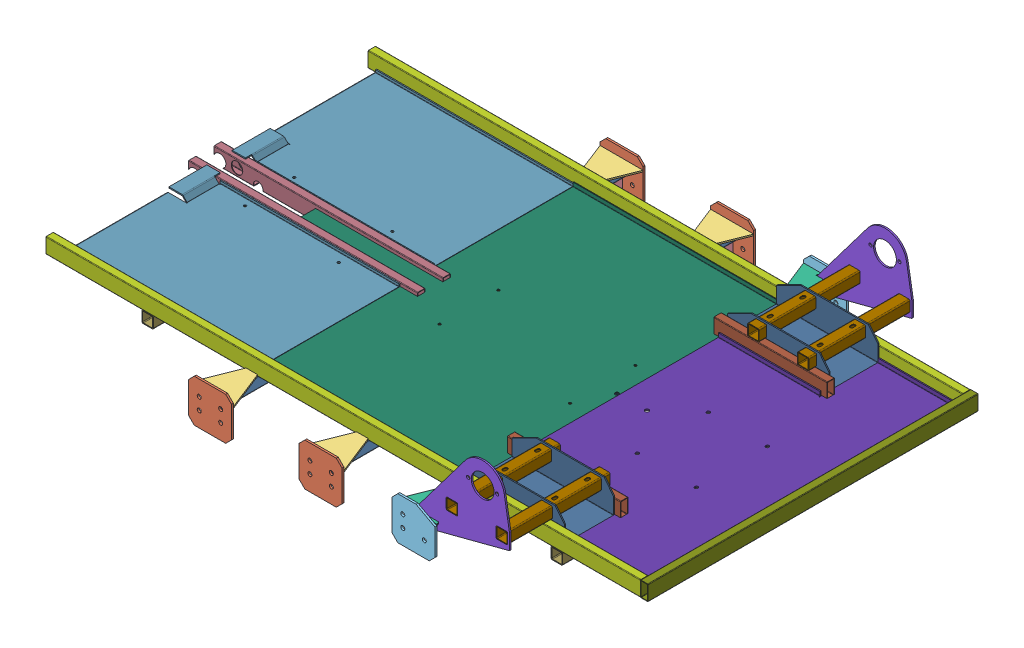
SolidWorks assembly ТП.016.01.01.01.00 - Рама корпуса, configuration 00. Lengths in mm.
Overall size (1585 284.02 1098).
72 component instances, 19 part files, 73 mates.
Components (placement in the parent):
- ТП.016.01.01.01.01.00 - Поперечная балка в сборе-1: ТП.016.01.01.01.01.00 - Поперечная балка в сборе [Центральная] at (824.8534 -30 544) size (112 110.77 1078)
  - ТП.016.01.01.01.01.01 - Поперечная балка (30х30)-1: ТП.016.01.01.01.01.01 - Поперечная балка (30х30) [--] at origin size (30 30 1068)
  - ТП.016.01.01.01.01.02 - Пластина кронштейна (5мм)-1: ТП.016.01.01.01.01.02 - Пластина кронштейна (5мм) [--] at (0 -56.7738 -5) size (112 110.77 5)
  - ТП.016.01.01.01.01.03 - Косынка верхняя (4мм)-1: ТП.016.01.01.01.01.03 - Косынка верхняя (4мм) [--] at (0 30 -10) size (112 4 104)
  - ТП.016.01.01.01.01.02 - Пластина кронштейна (5мм)-2: ТП.016.01.01.01.01.02 - Пластина кронштейна (5мм) [--] at (0 -56.7738 -1083) x (-1 0 0) z (0 0 -1) size (112 110.77 5)
  - ТП.016.01.01.01.01.03 - Косынка верхняя (4мм)-2: ТП.016.01.01.01.01.03 - Косынка верхняя (4мм) [--] at (0 30 -1078) x (-1 0 0) z (0 0 -1) size (112 4 104)
  - ТП.016.01.01.01.01.04 - Косынка нижняя (4мм)-2: ТП.016.01.01.01.01.04 - Косынка нижняя (4мм) [--] at (0 0 -1078) x (-1 0 0) z (0 0 -1) size (4 53.77 53.77)
  - ТП.016.01.01.01.01.04 - Косынка нижняя (4мм)-3: ТП.016.01.01.01.01.04 - Косынка нижняя (4мм) [--] at (0 0 -10) size (4 53.77 53.77)
  - ТП.016.01.01.01.01.05 - Пластина кронштейна задняя (5мм)-1: ТП.016.01.01.01.01.05 - Пластина кронштейна задняя (5мм) [--] at (0 -56.7738 -1083) x (-1 0 0) z (0 0 -1) size (112 110.77 5) (hidden)
  - ТП.016.01.01.01.01.06 - Косынка верхняя задняя (4мм)-1: ТП.016.01.01.01.01.06 - Косынка верхняя задняя (4мм) [--] at (-15 30 -1078) x (-1 0 0) z (0 0 -1) size (111.99 4 104) (hidden)
  - ТП.016.01.01.01.01.05 - Пластина кронштейна задняя (5мм)-2: ТП.016.01.01.01.01.05 - Пластина кронштейна задняя (5мм) [--] at (0 -56.7738 -10) x (-1 0 0) z (0 0 -1) size (112 110.77 5) (hidden)
  - ТП.016.01.01.01.01.06 - Косынка верхняя задняя (4мм)-2: ТП.016.01.01.01.01.06 - Косынка верхняя задняя (4мм) [--] at (-15 34 -10) x (-1 0 0) z (0 0 1) size (111.99 4 104) (hidden)
- ТП.016.01.01.01.01.00 - Поперечная балка в сборе-2: ТП.016.01.01.01.01.00 - Поперечная балка в сборе [Центральная] at (536.5267 -30 544) size (112 110.77 1078)
  - ТП.016.01.01.01.01.01 - Поперечная балка (30х30)-1: ТП.016.01.01.01.01.01 - Поперечная балка (30х30) [--] at origin size (30 30 1068)
  - ТП.016.01.01.01.01.02 - Пластина кронштейна (5мм)-1: ТП.016.01.01.01.01.02 - Пластина кронштейна (5мм) [--] at (0 -56.7738 -5) size (112 110.77 5)
  - ТП.016.01.01.01.01.03 - Косынка верхняя (4мм)-1: ТП.016.01.01.01.01.03 - Косынка верхняя (4мм) [--] at (0 30 -10) size (112 4 104)
  - ТП.016.01.01.01.01.02 - Пластина кронштейна (5мм)-2: ТП.016.01.01.01.01.02 - Пластина кронштейна (5мм) [--] at (0 -56.7738 -1083) x (-1 0 0) z (0 0 -1) size (112 110.77 5)
  - ТП.016.01.01.01.01.03 - Косынка верхняя (4мм)-2: ТП.016.01.01.01.01.03 - Косынка верхняя (4мм) [--] at (0 30 -1078) x (-1 0 0) z (0 0 -1) size (112 4 104)
  - ТП.016.01.01.01.01.04 - Косынка нижняя (4мм)-2: ТП.016.01.01.01.01.04 - Косынка нижняя (4мм) [--] at (0 0 -1078) x (-1 0 0) z (0 0 -1) size (4 53.77 53.77)
  - ТП.016.01.01.01.01.04 - Косынка нижняя (4мм)-3: ТП.016.01.01.01.01.04 - Косынка нижняя (4мм) [--] at (0 0 -10) size (4 53.77 53.77)
  - ТП.016.01.01.01.01.05 - Пластина кронштейна задняя (5мм)-1: ТП.016.01.01.01.01.05 - Пластина кронштейна задняя (5мм) [--] at (0 -56.7738 -1083) x (-1 0 0) z (0 0 -1) size (112 110.77 5) (hidden)
  - ТП.016.01.01.01.01.06 - Косынка верхняя задняя (4мм)-1: ТП.016.01.01.01.01.06 - Косынка верхняя задняя (4мм) [--] at (-15 30 -1078) x (-1 0 0) z (0 0 -1) size (111.99 4 104) (hidden)
  - ТП.016.01.01.01.01.05 - Пластина кронштейна задняя (5мм)-2: ТП.016.01.01.01.01.05 - Пластина кронштейна задняя (5мм) [--] at (0 -56.7738 -10) x (-1 0 0) z (0 0 -1) size (112 110.77 5) (hidden)
  - ТП.016.01.01.01.01.06 - Косынка верхняя задняя (4мм)-2: ТП.016.01.01.01.01.06 - Косынка верхняя задняя (4мм) [--] at (-15 34 -10) x (-1 0 0) z (0 0 1) size (111.99 4 104) (hidden)
- ТП.016.01.01.01.01.00 - Поперечная балка в сборе-3: ТП.016.01.01.01.01.00 - Поперечная балка в сборе [Задняя] at (1067.2668 -30 544) size (112 110.77 1078)
  - ТП.016.01.01.01.01.01 - Поперечная балка (30х30)-1: ТП.016.01.01.01.01.01 - Поперечная балка (30х30) [Под лебедку] at origin size (30 30 1068)
  - ТП.016.01.01.01.01.02 - Пластина кронштейна (5мм)-1: ТП.016.01.01.01.01.02 - Пластина кронштейна (5мм) [--] at (0 -56.7738 -5) size (112 110.77 5) (hidden)
  - ТП.016.01.01.01.01.03 - Косынка верхняя (4мм)-1: ТП.016.01.01.01.01.03 - Косынка верхняя (4мм) [--] at (0 30 -10) size (112 4 104) (hidden)
  - ТП.016.01.01.01.01.02 - Пластина кронштейна (5мм)-2: ТП.016.01.01.01.01.02 - Пластина кронштейна (5мм) [--] at (0 -56.7738 -1083) x (-1 0 0) z (0 0 -1) size (112 110.77 5) (hidden)
  - ТП.016.01.01.01.01.03 - Косынка верхняя (4мм)-2: ТП.016.01.01.01.01.03 - Косынка верхняя (4мм) [--] at (0 30 -1078) x (-1 0 0) z (0 0 -1) size (112 4 104) (hidden)
  - ТП.016.01.01.01.01.04 - Косынка нижняя (4мм)-2: ТП.016.01.01.01.01.04 - Косынка нижняя (4мм) [--] at (0 0 -1078) x (-1 0 0) z (0 0 -1) size (4 53.77 53.77)
  - ТП.016.01.01.01.01.04 - Косынка нижняя (4мм)-3: ТП.016.01.01.01.01.04 - Косынка нижняя (4мм) [--] at (0 0 -10) size (4 53.77 53.77)
  - ТП.016.01.01.01.01.05 - Пластина кронштейна задняя (5мм)-1: ТП.016.01.01.01.01.05 - Пластина кронштейна задняя (5мм) [--] at (0 -56.7738 -1083) x (-1 0 0) z (0 0 -1) size (112 110.77 5)
  - ТП.016.01.01.01.01.06 - Косынка верхняя задняя (4мм)-1: ТП.016.01.01.01.01.06 - Косынка верхняя задняя (4мм) [--] at (-15 30 -1078) x (-1 0 0) z (0 0 -1) size (111.99 4 104)
  - ТП.016.01.01.01.01.05 - Пластина кронштейна задняя (5мм)-2: ТП.016.01.01.01.01.05 - Пластина кронштейна задняя (5мм) [--] at (0 -56.7738 -10) x (-1 0 0) z (0 0 -1) size (112 110.77 5)
  - ТП.016.01.01.01.01.06 - Косынка верхняя задняя (4мм)-2: ТП.016.01.01.01.01.06 - Косынка верхняя задняя (4мм) [--] at (-15 34 -10) x (-1 0 0) z (0 0 1) size (111.99 4 104)
- ТП.016.01.01.01.02 - Балка платформы боковая (40х20)-1: ТП.016.01.01.01.02 - Балка платформы боковая (40х20) [--] at (250 0 -420) x (0 0 -1) z (1 0 0) size (20 40 1550)
- ТП.016.01.01.01.02 - Балка платформы боковая (40х20)-2: ТП.016.01.01.01.02 - Балка платформы боковая (40х20) [--] at (250 0 420) x (0 0 -1) z (1 0 0) size (20 40 1550)
- Схема рамы ЭСКИЗ-1: Схема рамы ЭСКИЗ [--] x (0 0 -1) z (1 0 0) size (559 0 1052.27)
- ТП.016.01.01.01.03.00 - Опора редуктора-1: ТП.016.01.01.01.03.00 - Опора редуктора [Правая] at (1235 143.2262 -526.5) x (-1 0 0) z (0 0 -1) size (276.73 227.25 267.34)
  - ТП.016.01.01.01.03.01 - Щека ведущей оси (4мм)-1: ТП.016.01.01.01.03.01 - Щека ведущей оси (4мм) [--] at origin size (249.73 227.25 4)
  - ТП.016.01.01.01.03.02 - Балка опоры ребуктора (30х30)-1: ТП.016.01.01.01.03.02 - Балка опоры ребуктора (30х30) [--] at (65 -72 0) size (30 30 267.34)
  - ТП.016.01.01.01.03.02 - Балка опоры ребуктора (30х30)-2: ТП.016.01.01.01.03.02 - Балка опоры ребуктора (30х30) [--] at (-65 -72 0) size (30 30 267.34)
  - ТП.016.01.01.01.03.02 - Балка опоры ребуктора (30х30)-3: ТП.016.01.01.01.03.02 - Балка опоры ребуктора (30х30) [--] at (95 -72 -4) x (-1 0 0) z (0 0 -1) size (30 30 267.34) (hidden)
  - ТП.016.01.01.01.03.02 - Балка опоры ребуктора (30х30)-4: ТП.016.01.01.01.03.02 - Балка опоры ребуктора (30х30) [--] at (-35 -72 -4) x (-1 0 0) z (0 0 -1) size (30 30 267.34) (hidden)
  - ТП.016.01.01.01.03.03 - Пол под редуктор (3мм)-1: ТП.016.01.01.01.03.03 - Пол под редуктор (3мм) [--] at (65 -143.2262 -181.9182) x (0 0 -1) z (1 0 0) size (130.84 76.23 264.73)
- ТП.016.01.01.01.03.00 - Опора редуктора-2: ТП.016.01.01.01.03.00 - Опора редуктора [Левая] at (1235 143.2262 522.5) x (-1 0 0) z (0 0 -1) size (276.73 227.25 267.34)
  - ТП.016.01.01.01.03.01 - Щека ведущей оси (4мм)-1: ТП.016.01.01.01.03.01 - Щека ведущей оси (4мм) [--] at origin size (249.73 227.25 4)
  - ТП.016.01.01.01.03.02 - Балка опоры ребуктора (30х30)-1: ТП.016.01.01.01.03.02 - Балка опоры ребуктора (30х30) [--] at (65 -72 0) size (30 30 267.34) (hidden)
  - ТП.016.01.01.01.03.02 - Балка опоры ребуктора (30х30)-2: ТП.016.01.01.01.03.02 - Балка опоры ребуктора (30х30) [--] at (-65 -72 0) size (30 30 267.34) (hidden)
  - ТП.016.01.01.01.03.02 - Балка опоры ребуктора (30х30)-3: ТП.016.01.01.01.03.02 - Балка опоры ребуктора (30х30) [--] at (95 -72 -4) x (-1 0 0) z (0 0 -1) size (30 30 267.34)
  - ТП.016.01.01.01.03.02 - Балка опоры ребуктора (30х30)-4: ТП.016.01.01.01.03.02 - Балка опоры ребуктора (30х30) [--] at (-35 -72 -4) x (-1 0 0) z (0 0 -1) size (30 30 267.34)
  - ТП.016.01.01.01.03.03 - Пол под редуктор (3мм)-1: ТП.016.01.01.01.03.03 - Пол под редуктор (3мм) [--] at (65 -143.2262 177.9182) x (0 0 -1) z (1 0 0) size (130.84 76.23 264.73)
- ТП.016.01.01.01.04 - Опора короткая под редуктор (40х20)-1: ТП.016.01.01.01.04 - Опора короткая под редуктор (40х20) [--] at (1052.2668 0 -259.1637) x (0 0 -1) z (1 0 0) size (20 40 294.73)
- ТП.016.01.01.01.04 - Опора короткая под редуктор (40х20)-2: ТП.016.01.01.01.04 - Опора короткая под редуктор (40х20) [--] at (1052.2668 0 279.1637) x (0 0 -1) z (1 0 0) size (20 40 294.73)
- ТП.016.01.01.01.05 - Поперечина короткая (30х30)-1: ТП.016.01.01.01.05 - Поперечина короткая (30х30) [--] at (1347 0 0) size (30 30 860)
- ТП.016.01.01.01.05 - Поперечина короткая (30х30)-2: ТП.016.01.01.01.05 - Поперечина короткая (30х30) [--] at (280 0 0) size (30 30 860)
- ТП.016.01.01.01.06 - Поддержка центральная (40х20)-1: ТП.016.01.01.01.06 - Поддержка центральная (40х20) [--] at (45 -9.1741 -23) x (0 0 1) z (-1 0 0) size (20 40 596.53)
- ТП.016.01.01.01.06 - Поддержка центральная (40х20)-2: ТП.016.01.01.01.06 - Поддержка центральная (40х20) [--] at (45 -9.1741 43) x (0 0 1) z (-1 0 0) size (20 40 596.53)
- ТП.016.01.01.01.07 - Пол перед (3мм)-1: ТП.016.01.01.01.07 - Пол перед (3мм) [Правый] at (0 0 -410) x (0 0 -1) z (1 0 0) size (377 29.49 517.11)
- ТП.016.01.01.01.07 - Пол перед (3мм)-2: ТП.016.01.01.01.07 - Пол перед (3мм) [Левый] at (0 0 -344) x (0 0 -1) z (1 0 0) size (754 29.49 517.11)
- ТП.016.01.01.01.08 - Пол центр (2мм)-1: ТП.016.01.01.01.08 - Пол центр (2мм) [--] at (250 0 0) x (0 0 -1) z (1 0 0) size (820 12 817.27)
- ТП.016.01.01.01.09 - Задний бампер (40х20)-1: ТП.016.01.01.01.09 - Задний бампер (40х20) [--] at (1570 0 0) size (20 40 860)
- ТП.016.01.01.01.10 - Пол капота (3мм)-1: ТП.016.01.01.01.10 - Пол капота (3мм) [--] at (1550 0 0) x (0 0 1) z (-1 0 0) size (820 13 482.73)
- Гайка (ГОСТ ISO 4032-2014)-1: Гайка (ГОСТ ISO 4032-2014) [Гайка М6 (ГОСТ ISO 4032)] at (153.1386 -2.6 64.0253) x (-0.998033 0 -0.062689) z (0 1 0) size (10 11.05 5.2)
- Гайка (ГОСТ ISO 4032-2014)-2: Гайка (ГОСТ ISO 4032-2014) [Гайка М6 (ГОСТ ISO 4032)] at (403.0634 -2.6 70.156) x (-0.991964 0 0.126519) z (0 1 0) size (10 11.05 5.2)
- Гайка (ГОСТ ISO 4032-2014)-3: Гайка (ГОСТ ISO 4032-2014) [Гайка М6 (ГОСТ ISO 4032)] at (672.9822 -2.6 76.7772) x (-0.941367 0 0.337385) z (0 1 0) size (10 11.05 5.2)
- Гайка (ГОСТ ISO 4032-2014)-4: Гайка (ГОСТ ISO 4032-2014) [Гайка М6 (ГОСТ ISO 4032)] at (1021.6211 -2.6 85.3294) x (-0.83604 0 0.548669) z (0 1 0) size (10 11.05 5.2)
- Гайка (ГОСТ ISO 4032-2014)-5: Гайка (ГОСТ ISO 4032-2014) [Гайка М6 (ГОСТ ISO 4032)] at (1021.6211 -2.6 -85.3294) x (-0.680834 0 0.732437) z (0 1 0) size (10 11.05 5.2)
- Гайка (ГОСТ ISO 4032-2014)-6: Гайка (ГОСТ ISO 4032-2014) [Гайка М6 (ГОСТ ISO 4032)] at (672.9822 -2.6 -76.7772) x (-0.498939 0 0.866637) z (0 1 0) size (10 11.05 5.2)
- Гайка (ГОСТ ISO 4032-2014)-7: Гайка (ГОСТ ISO 4032-2014) [Гайка М6 (ГОСТ ISO 4032)] at (403.0634 -2.6 -70.156) x (-0.323185 0 0.946336) z (0 1 0) size (10 11.05 5.2)
- Гайка (ГОСТ ISO 4032-2014)-8: Гайка (ГОСТ ISO 4032-2014) [Гайка М6 (ГОСТ ISO 4032)] at (153.1386 -2.6 -64.0253) x (-0.182176 0 0.983266) z (0 1 0) size (10 11.05 5.2)
Mates (geometry in assembly coordinates):
- Совпадение1: coincident: plane of ТП.016.01.01.01.01.00 - Поперечная балка в сборе-1/ТП.016.01.01.01.01.01 - Поперечная балка (30х30)-1 through (836.8534 0 -492.4264) normal (0 1 0); plane of ТП.016.01.01.01.01.00 - Поперечная балка в сборе-2/ТП.016.01.01.01.01.01 - Поперечная балка (30х30)-1 through (548.5267 0 -492.4264) normal (0 1 0)
- Совпадение2: coincident: plane of ТП.016.01.01.01.01.00 - Поперечная балка в сборе-1/ТП.016.01.01.01.01.02 - Пластина кронштейна (5мм)-2 through (824.8534 -86.7738 -539) normal (0 0 -1); plane of ТП.016.01.01.01.01.00 - Поперечная балка в сборе-2/ТП.016.01.01.01.01.02 - Пластина кронштейна (5мм)-2 through (536.5267 -86.7738 -539) normal (0 0 -1)
- Совпадение3: coincident: plane of ТП.016.01.01.01.01.00 - Поперечная балка в сборе-2/ТП.016.01.01.01.01.01 - Поперечная балка (30х30)-1 through (548.5267 0 -492.4264) normal (0 1 0); plane of ТП.016.01.01.01.01.00 - Поперечная балка в сборе-3/ТП.016.01.01.01.01.01 - Поперечная балка (30х30)-1 through (1079.2668 0 -492.4264) normal (0 1 0)
- Совпадение4: coincident: plane of ТП.016.01.01.01.01.00 - Поперечная балка в сборе-2/ТП.016.01.01.01.01.02 - Пластина кронштейна (5мм)-2 through (536.5267 -86.7738 -539) normal (0 0 -1); plane of ТП.016.01.01.01.01.00 - Поперечная балка в сборе-3/ТП.016.01.01.01.01.05 - Пластина кронштейна задняя (5мм)-1 through (1067.2668 -86.7738 -539) normal (0 0 -1)
- Совпадение5: coincident: plane of ТП.016.01.01.01.01.00 - Поперечная балка в сборе-1/ТП.016.01.01.01.01.01 - Поперечная балка (30х30)-1 through (836.8534 0 -492.4264) normal (0 1 0); plane of ТП.016.01.01.01.02 - Балка платформы боковая (40х20)-1 through (0 0 -411.5) normal (0 -1 0)
- Совпадение6: coincident: plane of ТП.016.01.01.01.01.00 - Поперечная балка в сборе-2/ТП.016.01.01.01.01.03 - Косынка верхняя (4мм)-2 through (521.5267 4 -430) normal (0 0 1); plane of ТП.016.01.01.01.02 - Балка платформы боковая (40х20)-1 through (0 38.5 -430) normal (0 0 -1)
- Совпадение7: coincident: plane of ТП.016.01.01.01.01.00 - Поперечная балка в сборе-2/ТП.016.01.01.01.01.01 - Поперечная балка (30х30)-1 through (548.5267 0 -492.4264) normal (0 1 0); plane of ТП.016.01.01.01.02 - Балка платформы боковая (40х20)-2 through (0 0 428.5) normal (0 -1 0)
- Совпадение8: coincident: plane of ТП.016.01.01.01.02 - Балка платформы боковая (40х20)-1 through (1550 38.5 -428.5) normal (1 0 0); plane of ТП.016.01.01.01.02 - Балка платформы боковая (40х20)-2 through (1550 38.5 411.5) normal (1 0 0)
- Совпадение9: coincident: plane of ТП.016.01.01.01.01.00 - Поперечная балка в сборе-2/ТП.016.01.01.01.01.03 - Косынка верхняя (4мм)-1 through (551.5267 4 430) normal (0 0 -1); plane of ТП.016.01.01.01.02 - Балка платформы боковая (40х20)-2 through (0 38.5 430) normal (0 0 1)
- Совпадение14: coincident: plane of Схема рамы ЭСКИЗ-1 through (0 0 0) normal (0 0 -1); plane of assembly through (0 0 0) normal (0 0 1)
- Совпадение15: coincident: plane of Схема рамы ЭСКИЗ-1 through (0 0 0) normal (0 1 0); plane of assembly through (0 0 0) normal (0 1 0)
- Совпадение16: coincident: plane of Схема рамы ЭСКИЗ-1 through (0 0 0) normal (1 0 0); plane of assembly through (0 0 0) normal (1 0 0)
- Совпадение17: coincident: plane of ТП.016.01.01.01.01.00 - Поперечная балка в сборе-1/ТП.016.01.01.01.01.01 - Поперечная балка (30х30)-1 through (809.8534 -27 -492.4264) normal (-1 0 0); line of Схема рамы ЭСКИЗ-1 through (809.8534 0 0) axis (0 0 -1)
- Совпадение18: coincident: plane of ТП.016.01.01.01.01.00 - Поперечная балка в сборе-1/ТП.016.01.01.01.01.01 - Поперечная балка (30х30)-1 through (836.8534 0 -492.4264) normal (0 1 0); plane of assembly through (0 0 0) normal (0 1 0)
- Совпадение19: coincident: plane of ТП.016.01.01.01.01.00 - Поперечная балка в сборе-3/ТП.016.01.01.01.01.01 - Поперечная балка (30х30)-1 through (1052.2668 -27 -492.4264) normal (-1 0 0); line of Схема рамы ЭСКИЗ-1 through (1052.2668 0 0) axis (0 0 -1)
- Совпадение20: coincident: plane of ТП.016.01.01.01.01.00 - Поперечная балка в сборе-2/ТП.016.01.01.01.01.01 - Поперечная балка (30х30)-1 through (521.5267 -27 -492.4264) normal (-1 0 0); line of Схема рамы ЭСКИЗ-1 through (521.5267 0 0) axis (0 0 -1)
- Совпадение21: coincident: plane of ТП.016.01.01.01.02 - Балка платформы боковая (40х20)-1 through (0 38.5 -428.5) normal (-1 0 0); point of Схема рамы ЭСКИЗ-1
- Симметричный1: symmetric: plane of ТП.016.01.01.01.01.00 - Поперечная балка в сборе-2/ТП.016.01.01.01.01.02 - Пластина кронштейна (5мм)-1 through (536.5267 -86.7738 539) normal (0 0 1); plane of ? through (536.5267 -86.7738 -539) normal (0 0 -1)
- Совпадение22: coincident: plane of ТП.016.01.01.01.01.00 - Поперечная балка в сборе-3/ТП.016.01.01.01.01.01 - Поперечная балка (30х30)-1 through (1082.2668 -27 -492.4264) normal (1 0 0); plane of ТП.016.01.01.01.03.00 - Опора редуктора-1/ТП.016.01.01.01.03.01 - Щека ведущей оси (4мм)-1 through (1082.2668 -3 -522.5) normal (-1 0 0)
- Совпадение23: coincident: plane of ТП.016.01.01.01.01.00 - Поперечная балка в сборе-3/ТП.016.01.01.01.01.01 - Поперечная балка (30х30)-1 through (1079.2668 0 -492.4264) normal (0 1 0); plane of ТП.016.01.01.01.03.00 - Опора редуктора-1/ТП.016.01.01.01.03.01 - Щека ведущей оси (4мм)-1 through (1055.2668 0 -522.5) normal (0 -1 0)
- Совпадение24: coincident: plane of ТП.016.01.01.01.01.00 - Поперечная балка в сборе-3/ТП.016.01.01.01.01.06 - Косынка верхняя задняя (4мм)-1 through (1079.2668 -3 -526.5) normal (0 0 1); plane of ТП.016.01.01.01.03.00 - Опора редуктора-1/ТП.016.01.01.01.03.01 - Щека ведущей оси (4мм)-1 through (1079.2668 -3 -526.5) normal (0 0 -1)
- Совпадение25: coincident: plane of ТП.016.01.01.01.01.00 - Поперечная балка в сборе-3/ТП.016.01.01.01.01.01 - Поперечная балка (30х30)-1 through (1082.2668 -27 -492.4264) normal (1 0 0); plane of ТП.016.01.01.01.03.00 - Опора редуктора-2/ТП.016.01.01.01.03.01 - Щека ведущей оси (4мм)-1 through (1082.2668 -3 526.5) normal (-1 0 0)
- Совпадение26: coincident: plane of ТП.016.01.01.01.01.00 - Поперечная балка в сборе-3/ТП.016.01.01.01.01.01 - Поперечная балка (30х30)-1 through (1079.2668 0 -492.4264) normal (0 1 0); plane of ТП.016.01.01.01.03.00 - Опора редуктора-2/ТП.016.01.01.01.03.01 - Щека ведущей оси (4мм)-1 through (1055.2668 0 526.5) normal (0 -1 0)
- Совпадение27: coincident: plane of ТП.016.01.01.01.01.00 - Поперечная балка в сборе-3/ТП.016.01.01.01.01.06 - Косынка верхняя задняя (4мм)-2 through (1079.2668 7 526.5) normal (0 0 -1); plane of ТП.016.01.01.01.03.00 - Опора редуктора-2/ТП.016.01.01.01.03.01 - Щека ведущей оси (4мм)-1 through (1079.2668 -3 526.5) normal (0 0 1)
- Совпадение28: coincident: plane of ТП.016.01.01.01.01.00 - Поперечная балка в сборе-3/ТП.016.01.01.01.01.01 - Поперечная балка (30х30)-1 through (1079.2668 0 -492.4264) normal (0 1 0); plane of ТП.016.01.01.01.04 - Опора короткая под редуктор (40х20)-1 through (1401.7214 0 -277.6637) normal (0 -1 0)
- Совпадение29: coincident: plane of ТП.016.01.01.01.03.00 - Опора редуктора-1/ТП.016.01.01.01.03.02 - Балка опоры ребуктора (30х30)-1 through (1133 215.2262 -259.1637) normal (0 0 1); plane of ТП.016.01.01.01.04 - Опора короткая под редуктор (40х20)-1 through (1401.7214 1.5 -259.1637) normal (0 0 1)
- Совпадение30: coincident: plane of ТП.016.01.01.01.01.00 - Поперечная балка в сборе-3/ТП.016.01.01.01.01.01 - Поперечная балка (30х30)-1 through (1052.2668 -27 -492.4264) normal (-1 0 0); plane of ТП.016.01.01.01.04 - Опора короткая под редуктор (40х20)-1 through (1052.2668 1.5 -260.6637) normal (-1 0 0)
- Совпадение31: coincident: plane of ТП.016.01.01.01.04 - Опора короткая под редуктор (40х20)-1 through (1401.7214 40 -277.6637) normal (0 1 0); plane of ТП.016.01.01.01.04 - Опора короткая под редуктор (40х20)-2 through (1401.7214 40 260.6637) normal (0 1 0)
- Совпадение32: coincident: plane of ТП.016.01.01.01.01.00 - Поперечная балка в сборе-3/ТП.016.01.01.01.01.01 - Поперечная балка (30х30)-1 through (1052.2668 -27 -492.4264) normal (-1 0 0); plane of ТП.016.01.01.01.04 - Опора короткая под редуктор (40х20)-2 through (1052.2668 1.5 277.6637) normal (-1 0 0)
- Совпадение33: coincident: plane of ТП.016.01.01.01.03.00 - Опора редуктора-2/ТП.016.01.01.01.03.02 - Балка опоры ребуктора (30х30)-4 through (1307 215.2262 259.1637) normal (0 0 -1); plane of ТП.016.01.01.01.04 - Опора короткая под редуктор (40х20)-2 through (1401.7214 1.5 259.1637) normal (0 0 -1)
- Совпадение34: coincident: plane of ТП.016.01.01.01.04 - Опора короткая под редуктор (40х20)-2 through (1401.7214 0 260.6637) normal (0 -1 0); plane of ТП.016.01.01.01.05 - Поперечина короткая (30х30)-1 through (1320 0 472.4264) normal (0 1 0)
- Совпадение35: coincident: plane of ТП.016.01.01.01.04 - Опора короткая под редуктор (40х20)-2 through (1347 170 293.1637) normal (1 0 0); plane of ТП.016.01.01.01.05 - Поперечина короткая (30х30)-1 through (1347 -3 472.4264) normal (1 0 0)
- Совпадение36: coincident: plane of ТП.016.01.01.01.02 - Балка платформы боковая (40х20)-2 through (0 38.5 430) normal (0 0 1); plane of ТП.016.01.01.01.05 - Поперечина короткая (30х30)-1 through (1114 38.5 430) normal (0 0 1)
- Совпадение37: coincident: plane of ТП.016.01.01.01.05 - Поперечина короткая (30х30)-1 through (1320 0 472.4264) normal (0 1 0); plane of ТП.016.01.01.01.05 - Поперечина короткая (30х30)-2 through (253 0 472.4264) normal (0 1 0)
- Совпадение38: coincident: point of ТП.016.01.01.01.02 - Балка платформы боковая (40х20)-2; plane of ТП.016.01.01.01.05 - Поперечина короткая (30х30)-2 through (250 -3 472.4264) normal (-1 0 0)
- Совпадение39: coincident: plane of ТП.016.01.01.01.02 - Балка платформы боковая (40х20)-2 through (0 38.5 430) normal (0 0 1); plane of ТП.016.01.01.01.05 - Поперечина короткая (30х30)-2 through (47 38.5 430) normal (0 0 1)
- Совпадение40: coincident: plane of ТП.016.01.01.01.05 - Поперечина короткая (30х30)-2 through (253 0 472.4264) normal (0 1 0); plane of ТП.016.01.01.01.06 - Поддержка центральная (40х20)-1 through (253 0 472.4264) normal (0 -1 0)
- Совпадение41: coincident: plane of ТП.016.01.01.01.01.00 - Поперечная балка в сборе-2/ТП.016.01.01.01.01.01 - Поперечная балка (30х30)-1 through (521.5267 -27 -492.4264) normal (-1 0 0); plane of ТП.016.01.01.01.06 - Поддержка центральная (40х20)-1 through (521.5267 -3 492.4264) normal (1 0 0)
- Совпадение42: coincident: plane of ТП.016.01.01.01.01.00 - Поперечная балка в сборе-2/ТП.016.01.01.01.01.01 - Поперечная балка (30х30)-1 through (521.5267 -27 -492.4264) normal (-1 0 0); plane of ТП.016.01.01.01.06 - Поддержка центральная (40х20)-2 through (521.5267 -3 558.4264) normal (1 0 0)
- Совпадение43: coincident: plane of ТП.016.01.01.01.06 - Поддержка центральная (40х20)-1 through (-15 10.8259 -24.5) normal (0 1 0); plane of ТП.016.01.01.01.06 - Поддержка центральная (40х20)-2 through (-15 10.8259 41.5) normal (0 1 0)
- Совпадение44: coincident: plane of ТП.016.01.01.01.05 - Поперечина короткая (30х30)-2 through (253 0 472.4264) normal (0 1 0); plane of ТП.016.01.01.01.07 - Пол перед (3мм)-1 through (0 0 -410) normal (0 -1 0)
- Совпадение45: coincident: plane of ТП.016.01.01.01.06 - Поддержка центральная (40х20)-1 through (-15 -27.6741 -43) normal (0 0 -1); plane of ТП.016.01.01.01.07 - Пол перед (3мм)-1 through (0 0 -43) normal (0 0 1)
- Совпадение47: coincident: plane of ТП.016.01.01.01.02 - Балка платформы боковая (40х20)-1 through (0 38.5 -410) normal (0 0 1); plane of ТП.016.01.01.01.07 - Пол перед (3мм)-1 through (0 0 -410) normal (0 0 -1)
- Симметричный2: symmetric: plane of ТП.016.01.01.01.01.00 - Поперечная балка в сборе-2/ТП.016.01.01.01.01.01 - Поперечная балка (30х30)-1 through (551.5267 -27 -492.4264) normal (1 0 0); plane of ТП.016.01.01.01.01.00 - Поперечная балка в сборе-2/ТП.016.01.01.01.01.01 - Поперечная балка (30х30)-1 through (521.5267 -27 -492.4264) normal (-1 0 0); plane of ТП.016.01.01.01.07 - Пол перед (3мм)-1 through (536.5267 3 -43) normal (1 0 0)
- Совпадение48: coincident: plane of ТП.016.01.01.01.05 - Поперечина короткая (30х30)-2 through (253 0 472.4264) normal (0 1 0); plane of ТП.016.01.01.01.07 - Пол перед (3мм)-2 through (0 0 410) normal (0 -1 0)
- Совпадение49: coincident: plane of ТП.016.01.01.01.02 - Балка платформы боковая (40х20)-2 through (0 38.5 410) normal (0 0 -1); plane of ТП.016.01.01.01.07 - Пол перед (3мм)-2 through (0 0 410) normal (0 0 1)
- Совпадение50: coincident: plane of ТП.016.01.01.01.07 - Пол перед (3мм)-1 through (536.5267 3 -43) normal (1 0 0); plane of ТП.016.01.01.01.07 - Пол перед (3мм)-2 through (536.5267 3 43) normal (1 0 0)
- Совпадение51: coincident: plane of ТП.016.01.01.01.06 - Поддержка центральная (40х20)-2 through (-15 -27.6741 43) normal (0 0 1); plane of ТП.016.01.01.01.07 - Пол перед (3мм)-2 through (0 0 43) normal (0 0 -1)
- Совпадение52: coincident: plane of ТП.016.01.01.01.01.00 - Поперечная балка в сборе-1/ТП.016.01.01.01.01.01 - Поперечная балка (30х30)-1 through (836.8534 0 -492.4264) normal (0 1 0); plane of ТП.016.01.01.01.08 - Пол центр (2мм)-1 through (250 0 0) normal (0 -1 0)
- Совпадение53: coincident: plane of ТП.016.01.01.01.02 - Балка платформы боковая (40х20)-1 through (0 38.5 -410) normal (0 0 1); plane of ТП.016.01.01.01.08 - Пол центр (2мм)-1 through (250 0 -410) normal (0 0 -1)
- Совпадение54: coincident: plane of ТП.016.01.01.01.06 - Поддержка центральная (40х20)-1 through (581.5267 -3 492.4264) normal (1 0 0); plane of ТП.016.01.01.01.08 - Пол центр (2мм)-1 through (581.5267 2 -23) normal (-1 0 0)
- Совпадение55: coincident: plane of ТП.016.01.01.01.02 - Балка платформы боковая (40х20)-1 through (0 40 -411.5) normal (0 1 0); plane of ТП.016.01.01.01.09 - Задний бампер (40х20)-1 through (1551.5 40 474.7214) normal (0 1 0)
- Совпадение56: coincident: plane of ТП.016.01.01.01.02 - Балка платформы боковая (40х20)-1 through (0 38.5 -430) normal (0 0 -1); plane of ТП.016.01.01.01.09 - Задний бампер (40х20)-1 through (3120 38.5 -430) normal (0 0 -1)
- Совпадение57: coincident: plane of ТП.016.01.01.01.02 - Балка платформы боковая (40х20)-1 through (1550 38.5 -428.5) normal (1 0 0); plane of ТП.016.01.01.01.09 - Задний бампер (40х20)-1 through (1550 38.5 474.7214) normal (-1 0 0)
- Совпадение58: coincident: plane of ТП.016.01.01.01.05 - Поперечина короткая (30х30)-1 through (1320 0 472.4264) normal (0 1 0); plane of ТП.016.01.01.01.10 - Пол капота (3мм)-1 through (1550 0 0) normal (0 -1 0)
- Совпадение59: coincident: plane of ТП.016.01.01.01.02 - Балка платформы боковая (40х20)-1 through (0 38.5 -410) normal (0 0 1); plane of ТП.016.01.01.01.10 - Пол капота (3мм)-1 through (1550 0 -410) normal (0 0 -1)
- Совпадение60: coincident: plane of ТП.016.01.01.01.08 - Пол центр (2мм)-1 through (1067.2668 2 -259.1637) normal (1 0 0); plane of ТП.016.01.01.01.10 - Пол капота (3мм)-1 through (1067.2668 3 0) normal (-1 0 0)
- Совпадение61: coincident: plane of ТП.016.01.01.01.07 - Пол перед (3мм)-2 through (0 0 410) normal (0 -1 0); plane of Гайка (ГОСТ ISO 4032-2014)-1 through (152.8597 0 68.4665) normal (0 1 0)
- Концентричный1: concentric: cylinder of ТП.016.01.01.01.07 - Пол перед (3мм)-2 through (153.1386 0 64.0253) axis (0 1 0) radius 3.25; cylinder of Гайка (ГОСТ ISO 4032-2014)-1 through (153.1386 150.1402 64.0253) axis (0 1 0) radius 2.134
- Совпадение62: coincident: plane of ТП.016.01.01.01.07 - Пол перед (3мм)-2 through (0 0 410) normal (0 -1 0); plane of Гайка (ГОСТ ISO 4032-2014)-2 through (403.6265 0 74.5702) normal (0 1 0)
- Концентричный2: concentric: cylinder of ТП.016.01.01.01.07 - Пол перед (3мм)-2 through (403.0634 0 70.156) axis (0 1 0) radius 3.25; cylinder of Гайка (ГОСТ ISO 4032-2014)-2 through (403.0634 150.1402 70.156) axis (0 1 0) radius 2.134
- Совпадение63: coincident: plane of ТП.016.01.01.01.07 - Пол перед (3мм)-2 through (0 0 410) normal (0 -1 0); plane of Гайка (ГОСТ ISO 4032-2014)-3 through (674.4836 0 80.9663) normal (0 1 0)
- Концентричный3: concentric: cylinder of ТП.016.01.01.01.08 - Пол центр (2мм)-1 through (672.9822 0 76.7772) axis (0 1 0) radius 3.25; cylinder of Гайка (ГОСТ ISO 4032-2014)-3 through (672.9822 150.1402 76.7772) axis (0 1 0) radius 2.134
- Совпадение64: coincident: plane of ТП.016.01.01.01.07 - Пол перед (3мм)-2 through (0 0 410) normal (0 -1 0); plane of Гайка (ГОСТ ISO 4032-2014)-4 through (1024.0627 0 89.0498) normal (0 1 0)
- Концентричный4: concentric: cylinder of ТП.016.01.01.01.08 - Пол центр (2мм)-1 through (1021.6211 0 85.3294) axis (0 1 0) radius 3.25; cylinder of Гайка (ГОСТ ISO 4032-2014)-4 through (1021.6211 150.1402 85.3294) axis (0 1 0) radius 2.134
- Совпадение65: coincident: plane of ТП.016.01.01.01.07 - Пол перед (3мм)-2 through (0 0 410) normal (0 -1 0); plane of Гайка (ГОСТ ISO 4032-2014)-5 through (1024.8804 0 -82.2997) normal (0 1 0)
- Концентричный5: concentric: cylinder of ТП.016.01.01.01.08 - Пол центр (2мм)-1 through (1021.6211 0 -85.3294) axis (0 1 0) radius 3.25; cylinder of Гайка (ГОСТ ISO 4032-2014)-5 through (1021.6211 150.1402 -85.3294) axis (0 1 0) radius 2.134
- Совпадение66: coincident: plane of ТП.016.01.01.01.07 - Пол перед (3мм)-2 through (0 0 410) normal (0 -1 0); plane of Гайка (ГОСТ ISO 4032-2014)-6 through (676.8388 0 -74.5569) normal (0 1 0)
- Концентричный6: concentric: cylinder of ТП.016.01.01.01.08 - Пол центр (2мм)-1 through (672.9822 0 -76.7772) axis (0 1 0) radius 3.25; cylinder of Гайка (ГОСТ ISO 4032-2014)-6 through (672.9822 150.1402 -76.7772) axis (0 1 0) radius 2.134
- Совпадение67: coincident: plane of ТП.016.01.01.01.07 - Пол перед (3мм)-2 through (0 0 410) normal (0 -1 0); plane of Гайка (ГОСТ ISO 4032-2014)-7 through (407.2746 0 -68.7178) normal (0 1 0)
- Концентричный7: concentric: cylinder of ТП.016.01.01.01.07 - Пол перед (3мм)-1 through (403.0634 0 -70.156) axis (0 1 0) radius 3.25; cylinder of Гайка (ГОСТ ISO 4032-2014)-7 through (403.0634 150.1402 -70.156) axis (0 1 0) radius 2.134
- Совпадение68: coincident: plane of ТП.016.01.01.01.07 - Пол перед (3мм)-2 through (0 0 410) normal (0 -1 0); plane of Гайка (ГОСТ ISO 4032-2014)-8 through (157.5142 0 -63.2146) normal (0 1 0)
- Концентричный8: concentric: cylinder of ТП.016.01.01.01.07 - Пол перед (3мм)-1 through (153.1386 0 -64.0253) axis (0 1 0) radius 3.25; cylinder of Гайка (ГОСТ ISO 4032-2014)-8 through (153.1386 150.1402 -64.0253) axis (0 1 0) radius 2.134
